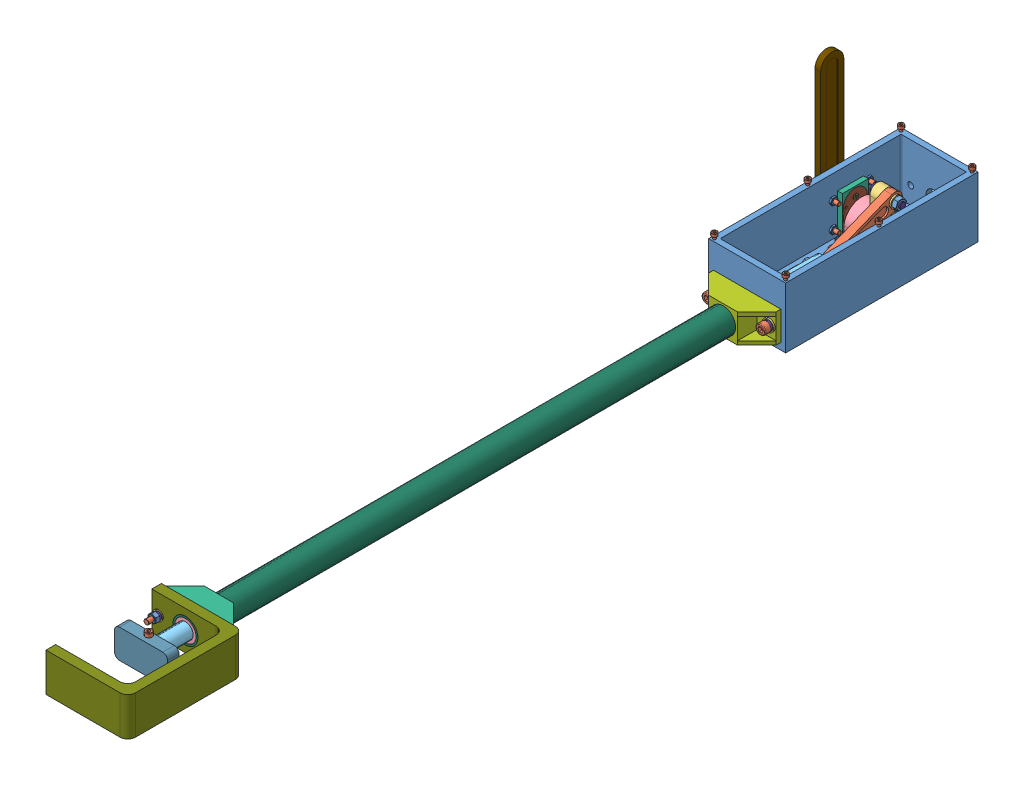
SolidWorks assembly 装夹部分, configuration 默认. Lengths in mm.
Overall size (109 161.6 894).
90 component instances, 28 part files, 159 mates.
Components (placement in the parent):
- 棘轮整体箱-1: 棘轮整体箱 [默认] at (-1.3808 -4.4563 300) size (80 63 200)
- 连杆2-1: 连杆2 [默认] at (6.6192 8.5437 195.581) x (1 0 0) z (0 -0.375 0.927025) size (8 16 96)
- 曲柄1-1: 曲柄1 [默认] at (-7.3808 8.5437 158.5) x (1 0 0) z (0 1 0) size (10 16 46)
- 棘轮轴承座-1: 棘轮轴承座 [默认] at (-17.3808 -24.4563 192) x (-1 0 0) z (0 0 -1) size (18 35 67)
- 棘轮光杆2-1: 棘轮光杆2 [默认] at (-1.3808 -6.4563 222.662) x (0 0 1) z (-1 0 0) size (703.5 16 16)
- 棘轮壳-1: 棘轮壳 [默认] at (-47.3808 1.8437 158.5) x (0 0 1) z (0 1 0) size (47 17 38)
- 棘轮轴-1: 棘轮轴 [默认] at (-33.3808 -6.4563 158.5) x (0 1 0) z (-1 0 0) size (22.6 22.6 63)
- 棘轮凸轮-1: 棘轮凸轮 [默认] at (-34.3808 7.3437 158.5) x (0 -0.826454 -0.563005) z (-1 0 0) size (8 16.5 15)
- 棘爪2-1: 棘爪2 [默认] at (-32.3808 11.8437 155.5) x (0 -0.832703 -0.55372) z (-1 0 0) size (11.61 3.86 13)
- 棘爪1-1: 棘爪1 [默认] at (-45.3808 11.8437 161.5) x (0 -0.838812 0.544421) z (1 0 0) size (11.61 3.86 13)
- 棘轮盖板-1: 棘轮盖板 [默认] at (-32.3808 -6.4563 158.5) x (0 0 1) z (1 0 0) size (25 34 2)
- cross recessed countersunk head screws gb1-1: cross recessed countersunk head screws gb1 [GB_CROSS_SCREWS_TYPE4 M3X10-8.35  H type-C] at (-29.7308 7.3437 158.5) x (-1 0 0) z (0 -0.924225 -0.381849) size (10 5.2 5.2)
- 圆锥弹簧-1: 圆锥弹簧 [默认] at (-38.3808 9.0284 150.4452) x (0.816495 -0.430855 -0.384316) z (-0.577352 -0.609319 -0.543503) size (8.02 1.7 8.11)
- 圆锥弹簧-2: 圆锥弹簧 [默认] at (-38.3808 9.0636 166.5942) x (0.838974 0.406094 -0.36223) z (-0.544172 0.626093 -0.558466) size (8.02 1.7 8.11)
- 顶片-1: 顶片 [默认] at (-1.3808 -6.4563 918.162) x (0 0 1) z (1 0 0) size (12 30 55)
- 棘轮箱杆-1: 棘轮箱杆 [默认] at (-1.3808 -6.4563 884) x (1 0 0) z (0 1 0) size (26 590 26)
- 抓手-1: 抓手 [默认] at (-36.3808 13.5437 874) x (0 -1 0) z (-1 0 0) size (40 120 85)
- 夹具销轴-1: 夹具销轴 [默认] at (-10.3808 23.5437 158.5) x (0 0 1) z (-1 0 0) size (10 12 29.2)
- 棘轮连接扳手-2: 棘轮连接扳手 [默认] at (-57.3808 -6.4563 158.5) x (0 0 -1) z (1 0 0) size (24 144 6)
- Aseembly M4X16-4: Aseembly M4X16 [默认] at (-34.9808 10.039 173.7157) x (0 0 -1) z (1 0 0) size (9.29 9.29 20)
  - hex nuts, style 1-grades ab gb-1: hex nuts, style 1-grades ab gb [GB_FASTENER_NUT_SNAB1 M4-C] at (-3.2843 0.5047 1.6) size (8.08 7 3.2)
  - hexagon socket head cap screws gb-1: hexagon socket head cap screws gb [GB_FASTENER_SCREWS_HSHCS M4X16-C] at (-3.2843 0.5047 -13.4) x (0 0 1) z (-0.418961 -0.908004 0) size (20 7 7)
  - plain washers-n series-grade a gb-1: plain washers-n series-grade a gb [GB_FASTENER_WASHER_PWNA 4] at (-3.2843 0.5047 -1.6) size (9 9 0.8)
- Aseembly M4X16-5: Aseembly M4X16 [默认] at (-34.9808 10.039 136.7157) x (0 0 -1) z (1 0 0) size (9.29 9.29 20)
  - hex nuts, style 1-grades ab gb-1: hex nuts, style 1-grades ab gb [GB_FASTENER_NUT_SNAB1 M4-C] at (-3.2843 0.5047 1.6) size (8.08 7 3.2)
  - hexagon socket head cap screws gb-1: hexagon socket head cap screws gb [GB_FASTENER_SCREWS_HSHCS M4X16-C] at (-3.2843 0.5047 -13.4) x (0 0 1) z (-0.418961 -0.908004 0) size (20 7 7)
  - plain washers-n series-grade a gb-1: plain washers-n series-grade a gb [GB_FASTENER_WASHER_PWNA 4] at (-3.2843 0.5047 -1.6) size (9 9 0.8)
- Aseembly M4X16-6: Aseembly M4X16 [默认] at (-34.9808 -15.961 136.7157) x (0 0 -1) z (1 0 0) size (9.29 9.29 20)
  - hex nuts, style 1-grades ab gb-1: hex nuts, style 1-grades ab gb [GB_FASTENER_NUT_SNAB1 M4-C] at (-3.2843 0.5047 1.6) size (8.08 7 3.2)
  - hexagon socket head cap screws gb-1: hexagon socket head cap screws gb [GB_FASTENER_SCREWS_HSHCS M4X16-C] at (-3.2843 0.5047 -13.4) x (0 0 1) z (-0.418961 -0.908004 0) size (20 7 7)
  - plain washers-n series-grade a gb-1: plain washers-n series-grade a gb [GB_FASTENER_WASHER_PWNA 4] at (-3.2843 0.5047 -1.6) size (9 9 0.8)
- Aseembly M4X16-7: Aseembly M4X16 [默认] at (-34.9808 -15.961 173.7157) x (0 0 -1) z (1 0 0) size (9.29 9.29 20)
  - hex nuts, style 1-grades ab gb-1: hex nuts, style 1-grades ab gb [GB_FASTENER_NUT_SNAB1 M4-C] at (-3.2843 0.5047 1.6) size (8.08 7 3.2)
  - hexagon socket head cap screws gb-1: hexagon socket head cap screws gb [GB_FASTENER_SCREWS_HSHCS M4X16-C] at (-3.2843 0.5047 -13.4) x (0 0 1) z (-0.418961 -0.908004 0) size (20 7 7)
  - plain washers-n series-grade a gb-1: plain washers-n series-grade a gb [GB_FASTENER_WASHER_PWNA 4] at (-3.2843 0.5047 -1.6) size (9 9 0.8)
- hexagon socket head cap screws gb-1: hexagon socket head cap screws gb [GB_FASTENER_SCREWS_HSHCS M5X25-C] at (-2.3808 -6.4563 145.5) x (0 0 1) z (-0.002807 0.999996 0) size (30 8.5 8.5)
- hex nuts, style 1-grades ab gb-2: hex nuts, style 1-grades ab gb [GB_FASTENER_NUT_SNAB1 M5-N] at (-2.3808 -6.4563 171.2) x (0.002807 -0.999996 0) z (0 0 1) size (9.24 8 4.7)
- 机箱滑动轴承16-22-1: 机箱滑动轴承16-22 [默认] at (-1.3808 -6.4563 296) x (0 0 -1) z (1 0 0) size (30 22 22)
- 机箱滑动轴承16-22-2: 机箱滑动轴承16-22 [默认] at (-1.3808 -6.4563 854) x (0 0 -1) z (0.444866 0.895597 0) size (30 22 22)
- hexagon socket head cap screws gb-2: hexagon socket head cap screws gb [GB_FASTENER_SCREWS_HSHCS M6X20-N] at (-17.3808 -36.0563 185) x (0 1 0) z (0.21636 0 0.976314) size (26 10 10)
- plain washers-n series-grade a gb-1: plain washers-n series-grade a gb [GB_FASTENER_WASHER_PWNA 6] at (-17.3808 -16.8563 185) x (0 0 -1) z (0 1 0) size (12 12 1.6)
- hex nuts, style 1-grades ab gb-3: hex nuts, style 1-grades ab gb [GB_FASTENER_NUT_SNAB1 M6-N] at (-17.3808 -11.6563 185) x (-0.789324 0 -0.613977) z (0 1 0) size (11.55 10 5.2)
- plain washers-n series-grade a gb-2: plain washers-n series-grade a gb [GB_FASTENER_WASHER_PWNA 6] at (-17.3808 -28.4563 185) x (0 0 -1) z (0 1 0) size (12 12 1.6)
- hexagon socket head cap screws gb-3: hexagon socket head cap screws gb [GB_FASTENER_SCREWS_HSHCS M6X20-N] at (-17.3808 -36.0563 132) x (0 1 0) z (0.21636 0 0.976314) size (26 10 10)
- plain washers-n series-grade a gb-3: plain washers-n series-grade a gb [GB_FASTENER_WASHER_PWNA 6] at (-17.3808 -28.4563 132) x (0 0 -1) z (0 1 0) size (12 12 1.6)
- hex nuts, style 1-grades ab gb-4: hex nuts, style 1-grades ab gb [GB_FASTENER_NUT_SNAB1 M6-N] at (-17.3808 -11.6563 132) x (-0.789324 0 -0.613977) z (0 1 0) size (11.55 10 5.2)
- plain washers-n series-grade a gb-4: plain washers-n series-grade a gb [GB_FASTENER_WASHER_PWNA 6] at (-17.3808 -16.8563 132) x (0 0 -1) z (0 1 0) size (12 12 1.6)
- 夹具销轴16-1: 夹具销轴16 [默认] at (-8.3808 -6.4563 232.662) x (0 0.733313 0.679892) z (-1 0 0) size (10 12 27.2)
- hex nuts, style 1-grades ab gb-5: hex nuts, style 1-grades ab gb [GB_FASTENER_NUT_SNAB1 M6-N] at (12.4192 23.5437 158.5) x (0 -0.789324 -0.613977) z (-1 0 0) size (11.55 10 5.2)
- plain washers-n series-grade a gb-5: plain washers-n series-grade a gb [GB_FASTENER_WASHER_PWNA 6] at (12.4192 23.5437 158.5) x (0 0 -1) z (1 0 0) size (12 12 1.6)
- plain washers-n series-grade a gb-6: plain washers-n series-grade a gb [GB_FASTENER_WASHER_PWNA 6] at (12.4192 -6.4563 232.662) x (0 0 -1) z (1 0 0) size (12 12 1.6)
- hex nuts, style 1-grades ab gb-6: hex nuts, style 1-grades ab gb [GB_FASTENER_NUT_SNAB1 M6-N] at (17.6192 -6.4563 232.662) x (0 0.789324 -0.613977) z (1 0 0) size (11.55 10 5.2)
- hexagon socket head cap screws gb-4: hexagon socket head cap screws gb [GB_FASTENER_SCREWS_HSHCS M4X35-C] at (-1.3808 12.5437 922.162) x (0 -1 0) z (0.903255 0 0.429104) size (39 7 7)
- hex nuts, style 1-grades ab gb-7: hex nuts, style 1-grades ab gb [GB_FASTENER_NUT_SNAB1 M4-C] at (-1.3808 -22.2563 922.162) x (1 0 0) z (0 1 0) size (8.08 7 3.2)
- plain washers-n series-grade a gb-7: plain washers-n series-grade a gb [GB_FASTENER_WASHER_PWNA 4] at (-1.3808 -21.4563 922.162) x (1 0 0) z (0 1 0) size (9 9 0.8)
- 焊接筒-1: 焊接筒 [默认] at (-1.3808 -6.4563 874) x (1 0 0) z (0 0 -1) size (70 30 25)
- 焊接筒2-1: 焊接筒2 [默认] at (-1.3808 -6.4563 300) size (70 30 25)
- hexagon socket head cap screws gb-5: hexagon socket head cap screws gb [GB_FASTENER_SCREWS_HSHCS M6X25-C] at (-29.3808 -6.4563 314.2) x (0 0 -1) z (1 0 0) size (31 10 10)
- plain washers-n series-grade a gb-8: plain washers-n series-grade a gb [GB_FASTENER_WASHER_PWNA 6] at (-29.3808 -6.4563 292.4) x (-1 0 0) z (0 0 -1) size (12 12 1.6)
- spring lock washers--normal type gb-1: spring lock washers--normal type gb [GB_FASTENER_WASHER_SW 6] at (-29.3808 -6.4563 290.8) x (-1 0 0) z (0 0 -1) size (9.88 9.88 1.6)
- hexagon socket head cap screws gb-6: hexagon socket head cap screws gb [GB_FASTENER_SCREWS_HSHCS M5X30-C] at (26.6192 -6.4563 861.7) x (0 0 1) z (-1 0 0) size (35 8.5 8.5)
- plain washers-n series-grade a gb-9: plain washers-n series-grade a gb [GB_FASTENER_WASHER_PWNA 5] at (26.6192 -6.4563 885) size (10 10 1)
- spring lock washers--normal type gb-2: spring lock washers--normal type gb [GB_FASTENER_WASHER_SW 5] at (26.6192 -6.4563 886.3) size (8 8 1.3)
- hex nuts, style 1-grades ab gb-8: hex nuts, style 1-grades ab gb [GB_FASTENER_NUT_SNAB1 M5-N] at (26.6192 -6.4563 891) size (9.24 8 4.7)
- hex nuts, style 1-grades ab gb-9: hex nuts, style 1-grades ab gb [GB_FASTENER_NUT_SNAB1 M6-N] at (-29.3808 -6.4563 285.6) x (-1 0 0) z (0 0 -1) size (11.55 10 5.2)
- hex nuts, style 1-grades ab gb-10: hex nuts, style 1-grades ab gb [GB_FASTENER_NUT_SNAB1 M6-N] at (26.6192 -6.4563 285.6) x (-1 0 0) z (0 0 -1) size (11.55 10 5.2)
- hexagon socket head cap screws gb-7: hexagon socket head cap screws gb [GB_FASTENER_SCREWS_HSHCS M6X25-C] at (26.6192 -6.4563 314.2) x (0 0 -1) z (1 0 0) size (31 10 10)
- plain washers-n series-grade a gb-10: plain washers-n series-grade a gb [GB_FASTENER_WASHER_PWNA 6] at (26.6192 -6.4563 305) x (-1 0 0) z (0 0 -1) size (12 12 1.6)
- spring lock washers--normal type gb-3: spring lock washers--normal type gb [GB_FASTENER_WASHER_SW 6] at (26.6192 -6.4563 306.6) x (-1 0 0) z (0 0 -1) size (9.88 9.88 1.6)
- hexagon socket head cap screws gb-8: hexagon socket head cap screws gb [GB_FASTENER_SCREWS_HSHCS M5X30-C] at (-29.3808 -6.4563 861.7) x (0 0 1) z (-1 0 0) size (35 8.5 8.5)
- plain washers-n series-grade a gb-11: plain washers-n series-grade a gb [GB_FASTENER_WASHER_PWNA 5] at (-29.3808 -6.4563 869) size (10 10 1)
- spring lock washers--normal type gb-4: spring lock washers--normal type gb [GB_FASTENER_WASHER_SW 5] at (-29.3808 -6.4563 886.3) size (8 8 1.3)
- hex nuts, style 1-grades ab gb-11: hex nuts, style 1-grades ab gb [GB_FASTENER_NUT_SNAB1 M5-N] at (-29.3808 -6.4563 891) x (0.819619 0.572908 0) z (0 0 1) size (9.24 8 4.7)
- plain washers-n series-grade a gb-12: plain washers-n series-grade a gb [GB_FASTENER_WASHER_PWNA 6] at (26.6192 -6.4563 292.4) x (-1 0 0) z (0 0 -1) size (12 12 1.6)
- spring lock washers--normal type gb-5: spring lock washers--normal type gb [GB_FASTENER_WASHER_SW 6] at (26.6192 -6.4563 290.8) x (-1 0 0) z (0 0 -1) size (9.88 9.88 1.6)
- spring lock washers--normal type gb-6: spring lock washers--normal type gb [GB_FASTENER_WASHER_SW 6] at (-29.3808 -6.4563 306.6) x (-1 0 0) z (0 0 -1) size (9.88 9.88 1.6)
- plain washers-n series-grade a gb-13: plain washers-n series-grade a gb [GB_FASTENER_WASHER_PWNA 6] at (-29.3808 -6.4563 305) x (-1 0 0) z (0 0 -1) size (12 12 1.6)
- plain washers-n series-grade a gb-14: plain washers-n series-grade a gb [GB_FASTENER_WASHER_PWNA 5] at (26.6192 -6.4563 869) size (10 10 1)
- spring lock washers--normal type gb-7: spring lock washers--normal type gb [GB_FASTENER_WASHER_SW 5] at (26.6192 -6.4563 868) size (8 8 1.3)
- plain washers-n series-grade a gb-15: plain washers-n series-grade a gb [GB_FASTENER_WASHER_PWNA 5] at (-29.3808 -6.4563 885) x (0.999691 -0.024859 0) z (0 0 1) size (10 10 1)
- spring lock washers--normal type gb-8: spring lock washers--normal type gb [GB_FASTENER_WASHER_SW 5] at (-29.3808 -6.4563 868) size (8 8 1.3)
- 棘轮箱盖板-1: 棘轮箱盖板 [默认] at (-1.3808 34.5437 200) x (0 0 1) z (0 1 0) size (200 80 3) (hidden)
- hexagon socket head cap screws gb-9: hexagon socket head cap screws gb [GB_FASTENER_SCREWS_HSHCS M3X10-C] at (35.6192 40.5437 297) x (0 -1 0) z (0 0 1) size (13 5.5 5.5)
- hexagon socket head cap screws gb-10: hexagon socket head cap screws gb [GB_FASTENER_SCREWS_HSHCS M3X10-C] at (-38.3808 40.5437 103) x (0 -1 0) z (0 0 1) size (13 5.5 5.5)
- hexagon socket head cap screws gb-11: hexagon socket head cap screws gb [GB_FASTENER_SCREWS_HSHCS M3X10-C] at (35.6192 40.5437 103) x (0 -1 0) z (0 0 1) size (13 5.5 5.5)
- hexagon socket head cap screws gb-12: hexagon socket head cap screws gb [GB_FASTENER_SCREWS_HSHCS M3X10-C] at (-38.3808 40.5437 200) x (0 -1 0) z (0 0 1) size (13 5.5 5.5)
- hexagon socket head cap screws gb-13: hexagon socket head cap screws gb [GB_FASTENER_SCREWS_HSHCS M3X10-C] at (35.6192 40.5437 200) x (0 -1 0) z (0 0 1) size (13 5.5 5.5)
- hexagon socket head cap screws gb-14: hexagon socket head cap screws gb [GB_FASTENER_SCREWS_HSHCS M3X10-C] at (-38.3808 40.5437 297) x (0 -1 0) z (0 0 1) size (13 5.5 5.5)
- cross recessed cheese head screws gb-1: cross recessed cheese head screws gb [GB_CROSS_SCREWS_TYPE2 M2.5X16-16  H type-C] at (-48.1808 1.8437 168) size (17.82 4.5 4.5)
- cross recessed cheese head screws gb-2: cross recessed cheese head screws gb [GB_CROSS_SCREWS_TYPE2 M2.5X16-16  H type-C] at (-48.1808 1.8437 149) size (17.82 4.5 4.5)
Mates (geometry in assembly coordinates):
- 同心1: concentric anti-aligned: cylinder of 棘轮整体箱-1 through (-17.3808 -34.4563 132) axis (0 1 0) radius 3.5; cylinder of 棘轮轴承座-1 through (-17.3808 -14.4563 132) axis (0 -1 0) radius 3.5
- 重合1: coincident aligned: circle of 棘轮整体箱-1; cylinder of 棘轮轴承座-1 through (-17.3808 -14.4563 185) axis (0 -1 0) radius 3.5
- 重合7: coincident anti-aligned: plane of 棘轮整体箱-1 through (-1.3808 -24.4563 300) normal (0 1 0); plane of 棘轮轴承座-1 through (-25.3808 -24.4563 125) normal (0 -1 0)
- 同心4: concentric aligned: cylinder of 曲柄1-1 through (2.6192 -6.4563 158.5) axis (-1 0 0) radius 5; cylinder of 棘轮轴承座-1 through (-2.3808 -6.4563 158.5) axis (-1 0 0) radius 5
- 同心5: concentric aligned: cylinder of 曲柄1-1 through (2.6192 23.5437 158.5) axis (-1 0 0) radius 4; cylinder of 连杆2-1 through (10.6192 23.5437 158.5) axis (-1 0 0) radius 4
- 重合4: coincident anti-aligned: plane of 连杆2-1 through (2.6192 8.5437 195.581) normal (-1 0 0); plane of 曲柄1-1 through (2.6192 23.5437 158.5) normal (1 0 0)
- 同心6: concentric aligned: cylinder of 棘轮光杆2-1 through (6.6192 -6.4563 232.662) axis (-1 0 0) radius 4; cylinder of 连杆2-1 through (10.6192 -6.4563 232.662) axis (-1 0 0) radius 4
- 同心7: concentric anti-aligned: cylinder of 棘轮整体箱-1 through (-1.3808 -6.4563 290) axis (0 0 1) radius 13; cylinder of 棘轮光杆2-1 through (-1.3808 -6.4563 926.162) axis (0 0 -1) radius 8
- 重合5: coincident anti-aligned: plane of 连杆2-1 through (2.6192 8.5437 195.581) normal (-1 0 0); plane of 棘轮光杆2-1 through (2.6192 3.5437 242.662) normal (1 0 0)
- 同心8: concentric anti-aligned: cylinder of 棘轮壳-1 through (-51.3808 10.5437 140) axis (1 0 0) radius 2.25; cylinder of 棘轮整体箱-1 through (-31.3808 10.5437 140) axis (-1 0 0) radius 2.25
- 同心9: concentric anti-aligned: cylinder of 棘轮整体箱-1 through (-31.3808 10.5437 177) axis (-1 0 0) radius 2.25; cylinder of 棘轮壳-1 through (-51.3808 10.5437 177) axis (1 0 0) radius 2.25
- 重合6: coincident anti-aligned: plane of 棘轮整体箱-1 through (-41.3808 -28.4563 100) normal (-1 0 0); plane of 棘轮壳-1 through (-41.3808 28.2056 172) normal (1 0 0)
- 同心10: concentric anti-aligned: cylinder of 棘轮壳-1 through (-44.3808 -6.4563 158.5) axis (-1 0 0) radius 7.5; cylinder of 棘轮轴-1 through (-33.3808 -6.4563 158.5) axis (1 0 0) radius 5
- 重合8: coincident anti-aligned: plane of 棘轮壳-1 through (-44.3808 1.8437 158.5) normal (1 0 0); plane of 棘轮轴-1 through (-44.3808 -6.4563 158.5) normal (-1 0 0)
- 同心11: concentric aligned: cylinder of 曲柄1-1 through (-2.3808 -6.4563 166.5) axis (0 0 -1) radius 2.5; cylinder of 棘轮轴-1 through (-2.3808 -6.4563 163.5) axis (0 0 -1) radius 2.5
- 同心12: concentric anti-aligned: cylinder of 棘轮壳-1 through (-44.3808 7.3437 158.5) axis (-1 0 0) radius 3.5; cylinder of 棘轮凸轮-1 through (-47.3808 7.3437 158.5) axis (1 0 0) radius 3.5
- 重合9: coincident anti-aligned: plane of 棘轮壳-1 through (-47.3808 1.8437 158.5) normal (-1 0 0); plane of 棘轮凸轮-1 through (-47.3808 7.3437 158.5) normal (1 0 0)
- 同心13: concentric anti-aligned: cylinder of 棘轮壳-1 through (-44.3808 11.8437 155.5) axis (-1 0 0) radius 1.5; cylinder of 棘爪2-1 through (-45.3808 11.8437 155.5) axis (1 0 0) radius 1.5
- 重合10: coincident anti-aligned: plane of 棘轮壳-1 through (-44.3808 1.8437 158.5) normal (1 0 0); plane of 棘爪2-1 through (-44.3808 11.8437 155.5) normal (-1 0 0)
- 同心14: concentric aligned: cylinder of 棘轮壳-1 through (-44.3808 11.8437 161.5) axis (-1 0 0) radius 1.5; cylinder of 棘爪1-1 through (-32.3808 11.8437 161.5) axis (-1 0 0) radius 1.5
- 重合11: coincident anti-aligned: plane of 棘轮壳-1 through (-44.3808 1.8437 158.5) normal (1 0 0); plane of 棘爪1-1 through (-44.3808 11.8437 161.5) normal (-1 0 0)
- 同心15: concentric anti-aligned: cylinder of 棘轮轴-1 through (-33.3808 -6.4563 158.5) axis (1 0 0) radius 5; cylinder of 棘轮盖板-1 through (-30.3808 -6.4563 158.5) axis (-1 0 0) radius 7.5
- 同心16: concentric anti-aligned: cylinder of 棘轮壳-1 through (-32.3808 2.5437 158.5) axis (1 0 0) radius 12.5; cylinder of 棘轮盖板-1 through (-30.3808 2.5437 158.5) axis (-1 0 0) radius 12.5
- 重合14: coincident anti-aligned: plane of 棘轮壳-1 through (-32.3808 -1.9563 158.5) normal (1 0 0); plane of 棘轮盖板-1 through (-32.3808 -1.9563 158.5) normal (-1 0 0)
- 同心19: concentric aligned: cylinder of 棘轮盖板-1 through (-30.3808 7.3437 158.5) axis (-1 0 0) radius 1.75; cylinder of cross recessed countersunk head screws gb1-1 through (-34.2466 7.3437 158.5) axis (-1 0 0) radius 1.5
- 重合17: coincident anti-aligned: plane of 棘轮盖板-1 through (-31.3808 7.3437 158.5) normal (1 0 0); circle of cross recessed countersunk head screws gb1-1
- 重合18: coincident aligned: line of 棘轮壳-1 through (-38.3808 12.1601 146.9343) axis (0 -0.665654 0.746261); line of 圆锥弹簧-1 through (-38.3808 9.0284 150.4452) axis (0 -0.665654 0.746261)
- 相切1: tangent: cylinder of 棘轮壳-1 through (-30.3808 0.5437 158.5) axis (-1 0 0) radius 11.5; face of 圆锥弹簧-1
- 重合19: coincident aligned: line of 棘轮壳-1 through (-38.3808 12.1601 170.0657) axis (0 -0.665654 -0.746261); line of 圆锥弹簧-2 through (-38.3808 9.0636 166.5942) axis (0 -0.665654 -0.746261)
- 相切2: tangent: cylinder of 棘轮壳-1 through (-30.3808 0.5437 158.5) axis (-1 0 0) radius 11.5; face of 圆锥弹簧-2
- 同心20: concentric anti-aligned: cylinder of 棘轮光杆2-1 through (-1.3808 -6.4563 926.162) axis (0 0 -1) radius 8; cylinder of 棘轮箱杆-1 through (-1.3808 -6.4563 294) axis (0 0 1) radius 13
- 重合20: coincident aligned: plane of 棘轮整体箱-1 through (-1.3808 -24.4563 294) normal (0 0 -1); plane of 棘轮箱杆-1 through (-1.3808 -6.4563 294) normal (0 0 -1)
- 同心24: concentric anti-aligned: cylinder of 棘轮箱杆-1 through (-1.3808 -6.4563 294) axis (0 0 1) radius 13; cylinder of 抓手-1 through (-1.3808 -6.4563 994.001) axis (0 0 -1) radius 13
- 重合22: coincident aligned: plane of 棘轮箱杆-1 through (-1.3808 -6.4563 884) normal (0 0 1); plane of 抓手-1 through (30.6192 -26.4563 884) normal (0 0 1)
- 同心26: concentric aligned: cylinder of 顶片-1 through (-1.3808 -6.4563 926.162) axis (0 0 -1) radius 8; circle of 抓手-1
- 平行1: parallel anti-aligned: plane of 抓手-1 through (-36.3808 -26.4563 884) normal (-1 0 0); plane of 棘轮整体箱-1 through (38.6192 -28.4563 100) normal (1 0 0)
- 同心27: concentric aligned: cylinder of 棘轮光杆2-1 through (-1.3808 -31.4563 922.162) axis (0 1 0) radius 2; cylinder of 顶片-1 through (-1.3808 -31.4563 922.162) axis (0 1 0) radius 2
- 同心28: concentric aligned: cylinder of 曲柄1-1 through (2.6192 23.5437 158.5) axis (-1 0 0) radius 4; cylinder of 夹具销轴-1 through (-10.3808 23.5437 158.5) axis (-1 0 0) radius 4
- 重合24: coincident anti-aligned: plane of 曲柄1-1 through (-7.3808 23.5437 158.5) normal (-1 0 0); plane of 夹具销轴-1 through (-7.3808 29.5437 158.5) normal (1 0 0)
- 重合26: coincident anti-aligned: plane of 棘轮轴-1 through (-67.3808 -1.7063 153.75) normal (0 0 -1); plane of 棘轮连接扳手-2 through (-54.3808 -1.7063 153.75) normal (0 0 1)
- 重合27: coincident aligned: plane of 棘轮轴-1 through (-60.3808 -6.4563 158.5) normal (-1 0 0); plane of 棘轮连接扳手-2 through (-60.3808 -6.4563 158.5) normal (-1 0 0)
- 重合28: coincident anti-aligned: plane of 棘轮轴-1 through (-67.3808 -11.2063 163.25) normal (0 -1 0); plane of 棘轮连接扳手-2 through (-54.3808 -11.2063 153.75) normal (0 1 0)
- 同心341: concentric aligned: cylinder of 棘轮壳-1 through (-44.3808 -15.4563 177) axis (-1 0 0) radius 4; cylinder of Aseembly M4X16-7/hexagon socket head cap screws gb-1 through (-28.3808 -15.4563 177) axis (-1 0 0) radius 2
- 重合341: coincident anti-aligned: circle of 棘轮壳-1; plane of Aseembly M4X16-7/hexagon socket head cap screws gb-1 through (-44.3808 -15.4563 177) normal (1 0 0)
- 同心351: concentric anti-aligned: cylinder of 棘轮壳-1 through (-51.3808 -15.4563 140) axis (1 0 0) radius 2.25; cylinder of Aseembly M4X16-6/hexagon socket head cap screws gb-1 through (-28.3808 -15.4563 140) axis (-1 0 0) radius 2
- 同心361: concentric anti-aligned: cylinder of 棘轮壳-1 through (-51.3808 10.5437 140) axis (1 0 0) radius 2.25; cylinder of Aseembly M4X16-5/hexagon socket head cap screws gb-1 through (-28.3808 10.5437 140) axis (-1 0 0) radius 2
- 重合351: coincident anti-aligned: plane of 棘轮壳-1 through (-44.3808 10.5437 140) normal (-1 0 0); plane of Aseembly M4X16-5/hexagon socket head cap screws gb-1 through (-44.3808 10.5437 140) normal (1 0 0)
- 重合361: coincident anti-aligned: plane of 棘轮壳-1 through (-44.3808 -15.4563 140) normal (-1 0 0); plane of Aseembly M4X16-6/hexagon socket head cap screws gb-1 through (-44.3808 -15.4563 140) normal (1 0 0)
- 同心411: concentric anti-aligned: cylinder of hexagon socket head cap screws gb-1 through (-2.3808 -6.4563 175.5) axis (0 0 -1) radius 2.5; cylinder of hex nuts, style 1-grades ab gb-2 through (-2.3808 -6.4563 166.5) axis (0 0 1) radius 2.067
- 同心421: concentric aligned: cylinder of 曲柄1-1 through (-2.3808 -6.4563 166.5) axis (0 0 -1) radius 2.5; cylinder of hexagon socket head cap screws gb-1 through (-2.3808 -6.4563 175.5) axis (0 0 -1) radius 2.5
- 重合391: coincident anti-aligned: plane of 曲柄1-1 through (2.6192 -6.4563 150.5) normal (0 0 -1); plane of hexagon socket head cap screws gb-1 through (-2.3808 -6.4563 150.5) normal (0 0 1)
- 重合401: coincident anti-aligned: plane of 曲柄1-1 through (2.6192 23.5437 166.5) normal (0 0 1); plane of hex nuts, style 1-grades ab gb-2 through (-2.3679 -11.0751 166.5) normal (0 0 -1)
- 重合42: coincident aligned: plane of 抓手-1 through (30.6192 -26.4563 884) normal (0 0 1); plane of 机箱滑动轴承16-22-2 through (-1.3808 -6.4563 884) normal (0 0 1)
- 同心422: concentric anti-aligned: cylinder of hexagon socket head cap screws gb-2 through (-17.3808 -10.0563 185) axis (0 -1 0) radius 3; cylinder of plain washers-n series-grade a gb-2 through (-17.3808 -30.0563 185) axis (0 1 0) radius 3.2
- 重合402: coincident anti-aligned: plane of hexagon socket head cap screws gb-2 through (-17.3808 -30.0563 185) normal (0 1 0); plane of plain washers-n series-grade a gb-2 through (-17.3808 -30.0563 185) normal (0 -1 0)
- 同心423: concentric anti-aligned: cylinder of hexagon socket head cap screws gb-2 through (-17.3808 -10.0563 185) axis (0 -1 0) radius 3; cylinder of plain washers-n series-grade a gb-1 through (-17.3808 -18.4563 185) axis (0 1 0) radius 3.2
- 同心424: concentric anti-aligned: cylinder of hexagon socket head cap screws gb-2 through (-17.3808 -10.0563 185) axis (0 -1 0) radius 3; cylinder of hex nuts, style 1-grades ab gb-3 through (-17.3808 -16.8563 185) axis (0 1 0) radius 2.4585
- 重合403: coincident anti-aligned: plane of plain washers-n series-grade a gb-1 through (-17.3808 -16.8563 185) normal (0 1 0); plane of hex nuts, style 1-grades ab gb-3 through (-11.2411 -16.8563 177.1068) normal (0 -1 0)
- 同心425: concentric aligned: cylinder of 棘轮轴承座-1 through (-17.3808 -14.4563 185) axis (0 -1 0) radius 3.5; cylinder of hexagon socket head cap screws gb-2 through (-17.3808 -10.0563 185) axis (0 -1 0) radius 3
- 重合404: coincident aligned: plane of 棘轮轴承座-1 through (-2.3808 -18.4563 192) normal (0 1 0); circle of plain washers-n series-grade a gb-1
- 重合405: coincident anti-aligned: plane of 棘轮整体箱-1 through (-41.3808 -28.4563 100) normal (0 -1 0); circle of plain washers-n series-grade a gb-2
- 同心426: concentric anti-aligned: cylinder of hexagon socket head cap screws gb-3 through (-17.3808 -10.0563 132) axis (0 -1 0) radius 3; cylinder of plain washers-n series-grade a gb-3 through (-17.3808 -30.0563 132) axis (0 1 0) radius 3.2
- 重合406: coincident anti-aligned: plane of hexagon socket head cap screws gb-3 through (-17.3808 -30.0563 132) normal (0 1 0); plane of plain washers-n series-grade a gb-3 through (-17.3808 -30.0563 132) normal (0 -1 0)
- 重合407: coincident anti-aligned: plane of 棘轮整体箱-1 through (-41.3808 -28.4563 100) normal (0 -1 0); plane of plain washers-n series-grade a gb-3 through (-17.3808 -28.4563 132) normal (0 1 0)
- 同心427: concentric anti-aligned: cylinder of 棘轮整体箱-1 through (-17.3808 -34.4563 132) axis (0 1 0) radius 3.5; cylinder of hexagon socket head cap screws gb-3 through (-17.3808 -10.0563 132) axis (0 -1 0) radius 3
- 同心428: concentric aligned: cylinder of hex nuts, style 1-grades ab gb-4 through (-17.3808 -16.8563 132) axis (0 1 0) radius 2.4585; cylinder of plain washers-n series-grade a gb-4 through (-17.3808 -18.4563 132) axis (0 1 0) radius 3.2
- 重合408: coincident anti-aligned: plane of hex nuts, style 1-grades ab gb-4 through (-11.2411 -16.8563 124.1068) normal (0 -1 0); plane of plain washers-n series-grade a gb-4 through (-17.3808 -16.8563 132) normal (0 1 0)
- 重合409: coincident anti-aligned: plane of 棘轮轴承座-1 through (-2.3808 -18.4563 192) normal (0 1 0); plane of plain washers-n series-grade a gb-4 through (-17.3808 -18.4563 132) normal (0 -1 0)
- 同心429: concentric anti-aligned: cylinder of hexagon socket head cap screws gb-3 through (-17.3808 -10.0563 132) axis (0 -1 0) radius 3; cylinder of hex nuts, style 1-grades ab gb-4 through (-17.3808 -16.8563 132) axis (0 1 0) radius 2.4585
- 同心430: concentric aligned: cylinder of 连杆2-1 through (10.6192 -6.4563 232.662) axis (-1 0 0) radius 8; cylinder of 夹具销轴16-1 through (-8.3808 -6.4563 232.662) axis (-1 0 0) radius 4
- 同心431: concentric aligned: cylinder of 棘轮光杆2-1 through (6.6192 -6.4563 232.662) axis (-1 0 0) radius 4; cylinder of 夹具销轴16-1 through (-8.3808 -6.4563 232.662) axis (-1 0 0) radius 4
- 重合410: coincident anti-aligned: plane of 棘轮光杆2-1 through (-5.3808 3.5437 242.662) normal (-1 0 0); plane of 夹具销轴16-1 through (-5.3808 -2.377 228.2621) normal (1 0 0)
- 重合411: coincident anti-aligned: cylinder of 夹具销轴-1 through (-10.3808 23.5437 158.5) axis (-1 0 0) radius 3; circle of hex nuts, style 1-grades ab gb-5
- 同心435: concentric anti-aligned: cylinder of 夹具销轴-1 through (-10.3808 23.5437 158.5) axis (-1 0 0) radius 3; cylinder of plain washers-n series-grade a gb-5 through (10.8192 23.5437 158.5) axis (1 0 0) radius 6
- 重合412: coincident anti-aligned: plane of 夹具销轴-1 through (10.8192 27.5437 158.5) normal (1 0 0); plane of plain washers-n series-grade a gb-5 through (10.8192 23.5437 158.5) normal (-1 0 0)
- 重合413: coincident anti-aligned: plane of hex nuts, style 1-grades ab gb-5 through (12.4192 29.6835 150.6068) normal (-1 0 0); plane of plain washers-n series-grade a gb-5 through (12.4192 23.5437 158.5) normal (1 0 0)
- 同心436: concentric aligned: cylinder of plain washers-n series-grade a gb-6 through (10.8192 -6.4563 232.662) axis (1 0 0) radius 3.2; cylinder of hex nuts, style 1-grades ab gb-6 through (12.4192 -6.4563 232.662) axis (1 0 0) radius 2.4585
- 同心437: concentric anti-aligned: cylinder of 夹具销轴16-1 through (-8.3808 -6.4563 232.662) axis (-1 0 0) radius 3; cylinder of hex nuts, style 1-grades ab gb-6 through (12.4192 -6.4563 232.662) axis (1 0 0) radius 2.4585
- 重合414: coincident anti-aligned: plane of plain washers-n series-grade a gb-6 through (10.8192 -6.4563 232.662) normal (-1 0 0); plane of 夹具销轴16-1 through (10.8192 -3.7367 229.7287) normal (1 0 0)
- 重合415: coincident anti-aligned: plane of plain washers-n series-grade a gb-6 through (12.4192 -6.4563 232.662) normal (1 0 0); plane of hex nuts, style 1-grades ab gb-6 through (12.4192 -12.5961 224.7687) normal (-1 0 0)
- 同心439: concentric aligned: cylinder of 顶片-1 through (-1.3808 -31.4563 922.162) axis (0 1 0) radius 2; cylinder of hexagon socket head cap screws gb-4 through (-1.3808 -26.4563 922.162) axis (0 1 0) radius 2
- 重合417: coincident anti-aligned: plane of 顶片-1 through (21.1192 8.5437 930.162) normal (0 1 0); plane of hexagon socket head cap screws gb-4 through (-1.3808 8.5437 922.162) normal (0 -1 0)
- 同心440: concentric aligned: cylinder of hex nuts, style 1-grades ab gb-7 through (-1.3808 -25.4563 922.162) axis (0 1 0) radius 1.621; cylinder of plain washers-n series-grade a gb-7 through (-1.3808 -22.2563 922.162) axis (0 1 0) radius 2.15
- 重合418: coincident anti-aligned: plane of hex nuts, style 1-grades ab gb-7 through (2.6606 -22.2563 922.162) normal (0 1 0); plane of plain washers-n series-grade a gb-7 through (-1.3808 -22.2563 922.162) normal (0 -1 0)
- 同心441: concentric aligned: cylinder of hexagon socket head cap screws gb-4 through (-1.3808 -26.4563 922.162) axis (0 1 0) radius 2; cylinder of hex nuts, style 1-grades ab gb-7 through (-1.3808 -25.4563 922.162) axis (0 1 0) radius 1.621
- 重合419: coincident anti-aligned: plane of 顶片-1 through (21.1192 -21.4563 930.162) normal (0 -1 0); plane of plain washers-n series-grade a gb-7 through (-1.3808 -21.4563 922.162) normal (0 1 0)
- 同心442: concentric anti-aligned: cylinder of 焊接筒-1 through (26.6192 -6.4563 869) axis (0 0 1) radius 2.75; cylinder of 抓手-1 through (26.6192 -6.4563 894) axis (0 0 -1) radius 3.25
- 同心443: concentric anti-aligned: cylinder of 焊接筒-1 through (-29.3808 -6.4563 869) axis (0 0 1) radius 2.75; cylinder of 抓手-1 through (-29.3808 -6.4563 894) axis (0 0 -1) radius 3.25
- 重合420: coincident anti-aligned: plane of 抓手-1 through (-36.3808 -26.4563 874) normal (0 0 -1); plane of 焊接筒-1 through (-1.3808 -6.4563 874) normal (0 0 1)
- 同心444: concentric anti-aligned: cylinder of 棘轮整体箱-1 through (26.6192 -6.4563 290) axis (0 0 1) radius 3.3; cylinder of 焊接筒2-1 through (26.6192 -6.4563 305) axis (0 0 -1) radius 3.3
- 同心445: concentric anti-aligned: cylinder of 棘轮整体箱-1 through (-29.3808 -6.4563 290) axis (0 0 1) radius 3.3; cylinder of 焊接筒2-1 through (-29.3808 -6.4563 305) axis (0 0 -1) radius 3.3
- 重合421: coincident: plane of 棘轮整体箱-1 through (-1.3808 -4.4563 300) normal (0 0 1); line of 焊接筒2-1 through (33.6192 8.5437 300) axis (-1 0 0)
- 同心446: concentric anti-aligned: cylinder of hexagon socket head cap screws gb-7 through (26.6192 -6.4563 283.2) axis (0 0 1) radius 3; cylinder of plain washers-n series-grade a gb-10 through (26.6192 -6.4563 306.6) axis (0 0 -1) radius 3.2
- 同心447: concentric anti-aligned: cylinder of hexagon socket head cap screws gb-7 through (26.6192 -6.4563 283.2) axis (0 0 1) radius 3; cylinder of spring lock washers--normal type gb-3 through (26.6192 -6.4563 308.2) axis (0 0 -1) radius 3.34
- 重合422: coincident anti-aligned: plane of plain washers-n series-grade a gb-10 through (26.6192 -6.4563 306.6) normal (0 0 1); plane of spring lock washers--normal type gb-3 through (26.6192 -6.4563 306.6) normal (0 0 -1)
- 重合423: coincident anti-aligned: plane of hexagon socket head cap screws gb-7 through (26.6192 -6.4563 308.2) normal (0 0 -1); plane of spring lock washers--normal type gb-3 through (26.6192 -6.4563 308.2) normal (0 0 1)
- 同心448: concentric anti-aligned: cylinder of hex nuts, style 1-grades ab gb-10 through (26.6192 -6.4563 290.8) axis (0 0 -1) radius 2.4585; cylinder of hexagon socket head cap screws gb-7 through (26.6192 -6.4563 283.2) axis (0 0 1) radius 3
- 同心449: concentric anti-aligned: cylinder of hexagon socket head cap screws gb-7 through (26.6192 -6.4563 283.2) axis (0 0 1) radius 3; cylinder of plain washers-n series-grade a gb-12 through (26.6192 -6.4563 294) axis (0 0 -1) radius 3.2
- 同心450: concentric anti-aligned: cylinder of hexagon socket head cap screws gb-7 through (26.6192 -6.4563 283.2) axis (0 0 1) radius 3; cylinder of spring lock washers--normal type gb-5 through (26.6192 -6.4563 292.4) axis (0 0 -1) radius 3.34
- 重合425: coincident anti-aligned: plane of plain washers-n series-grade a gb-12 through (26.6192 -6.4563 292.4) normal (0 0 -1); plane of spring lock washers--normal type gb-5 through (26.6192 -6.4563 292.4) normal (0 0 1)
- 重合426: coincident anti-aligned: plane of hex nuts, style 1-grades ab gb-10 through (26.6192 -16.4563 290.8) normal (0 0 1); plane of spring lock washers--normal type gb-5 through (26.6192 -6.4563 290.8) normal (0 0 -1)
- 同心451: concentric anti-aligned: cylinder of 焊接筒2-1 through (26.6192 -6.4563 305) axis (0 0 -1) radius 3.3; cylinder of hexagon socket head cap screws gb-7 through (26.6192 -6.4563 283.2) axis (0 0 1) radius 3
- 重合427: coincident anti-aligned: plane of 焊接筒2-1 through (-1.3808 -6.4563 305) normal (0 0 1); plane of plain washers-n series-grade a gb-10 through (26.6192 -6.4563 305) normal (0 0 -1)
- 重合428: coincident anti-aligned: plane of 棘轮整体箱-1 through (-1.3808 -24.4563 294) normal (0 0 -1); plane of plain washers-n series-grade a gb-12 through (26.6192 -6.4563 294) normal (0 0 1)
- 同心452: concentric anti-aligned: cylinder of hexagon socket head cap screws gb-5 through (-29.3808 -6.4563 283.2) axis (0 0 1) radius 3; cylinder of plain washers-n series-grade a gb-8 through (-29.3808 -6.4563 294) axis (0 0 -1) radius 3.2
- 同心453: concentric anti-aligned: cylinder of hexagon socket head cap screws gb-5 through (-29.3808 -6.4563 283.2) axis (0 0 1) radius 3; cylinder of spring lock washers--normal type gb-1 through (-29.3808 -6.4563 292.4) axis (0 0 -1) radius 3.34
- 同心454: concentric anti-aligned: cylinder of hexagon socket head cap screws gb-5 through (-29.3808 -6.4563 283.2) axis (0 0 1) radius 3; cylinder of hex nuts, style 1-grades ab gb-9 through (-29.3808 -6.4563 290.8) axis (0 0 -1) radius 2.4585
- 重合429: coincident anti-aligned: plane of spring lock washers--normal type gb-1 through (-29.3808 -6.4563 290.8) normal (0 0 -1); plane of hex nuts, style 1-grades ab gb-9 through (-29.3808 -16.4563 290.8) normal (0 0 1)
- 重合430: coincident anti-aligned: plane of plain washers-n series-grade a gb-8 through (-29.3808 -6.4563 292.4) normal (0 0 -1); plane of spring lock washers--normal type gb-1 through (-29.3808 -6.4563 292.4) normal (0 0 1)
- 同心455: concentric anti-aligned: cylinder of hexagon socket head cap screws gb-5 through (-29.3808 -6.4563 283.2) axis (0 0 1) radius 3; cylinder of plain washers-n series-grade a gb-13 through (-29.3808 -6.4563 306.6) axis (0 0 -1) radius 3.2
- 同心456: concentric anti-aligned: cylinder of hexagon socket head cap screws gb-5 through (-29.3808 -6.4563 283.2) axis (0 0 1) radius 3; cylinder of spring lock washers--normal type gb-6 through (-29.3808 -6.4563 308.2) axis (0 0 -1) radius 3.34
- 重合431: coincident anti-aligned: plane of spring lock washers--normal type gb-6 through (-29.3808 -6.4563 306.6) normal (0 0 -1); plane of plain washers-n series-grade a gb-13 through (-29.3808 -6.4563 306.6) normal (0 0 1)
- 重合432: coincident anti-aligned: plane of hexagon socket head cap screws gb-5 through (-29.3808 -6.4563 308.2) normal (0 0 -1); plane of spring lock washers--normal type gb-6 through (-29.3808 -6.4563 308.2) normal (0 0 1)
- 同心457: concentric anti-aligned: cylinder of 焊接筒2-1 through (-29.3808 -6.4563 305) axis (0 0 -1) radius 3.3; cylinder of hexagon socket head cap screws gb-5 through (-29.3808 -6.4563 283.2) axis (0 0 1) radius 3
- 重合433: coincident anti-aligned: plane of 焊接筒2-1 through (-1.3808 -6.4563 305) normal (0 0 1); plane of plain washers-n series-grade a gb-13 through (-29.3808 -6.4563 305) normal (0 0 -1)
- 重合434: coincident anti-aligned: plane of 棘轮整体箱-1 through (-1.3808 -24.4563 294) normal (0 0 -1); plane of plain washers-n series-grade a gb-8 through (-29.3808 -6.4563 294) normal (0 0 1)
- 同心458: concentric anti-aligned: cylinder of hexagon socket head cap screws gb-6 through (26.6192 -6.4563 896.7) axis (0 0 -1) radius 2.5; cylinder of plain washers-n series-grade a gb-9 through (26.6192 -6.4563 884) axis (0 0 1) radius 2.65
- 同心459: concentric anti-aligned: cylinder of hexagon socket head cap screws gb-6 through (26.6192 -6.4563 896.7) axis (0 0 -1) radius 2.5; cylinder of spring lock washers--normal type gb-2 through (26.6192 -6.4563 885) axis (0 0 1) radius 2.7
- 同心460: concentric anti-aligned: cylinder of hexagon socket head cap screws gb-6 through (26.6192 -6.4563 896.7) axis (0 0 -1) radius 2.5; cylinder of plain washers-n series-grade a gb-14 through (26.6192 -6.4563 868) axis (0 0 1) radius 2.65
- 同心461: concentric anti-aligned: cylinder of hexagon socket head cap screws gb-6 through (26.6192 -6.4563 896.7) axis (0 0 -1) radius 2.5; cylinder of spring lock washers--normal type gb-7 through (26.6192 -6.4563 866.7) axis (0 0 1) radius 2.7
- 同心462: concentric anti-aligned: cylinder of hexagon socket head cap screws gb-6 through (26.6192 -6.4563 896.7) axis (0 0 -1) radius 2.5; cylinder of hex nuts, style 1-grades ab gb-8 through (26.6192 -6.4563 886.3) axis (0 0 1) radius 2.067
- 重合435: coincident anti-aligned: plane of plain washers-n series-grade a gb-14 through (26.6192 -6.4563 868) normal (0 0 -1); plane of spring lock washers--normal type gb-7 through (26.6192 -6.4563 868) normal (0 0 1)
- 重合436: coincident anti-aligned: plane of hexagon socket head cap screws gb-6 through (26.6192 -6.4563 866.7) normal (0 0 1); plane of spring lock washers--normal type gb-7 through (26.6192 -6.4563 866.7) normal (0 0 -1)
- 重合437: coincident anti-aligned: plane of spring lock washers--normal type gb-2 through (26.6192 -6.4563 886.3) normal (0 0 1); plane of hex nuts, style 1-grades ab gb-8 through (31.238 -6.4563 886.3) normal (0 0 -1)
- 重合438: coincident anti-aligned: plane of plain washers-n series-grade a gb-9 through (26.6192 -6.4563 885) normal (0 0 1); plane of spring lock washers--normal type gb-2 through (26.6192 -6.4563 885) normal (0 0 -1)
- 同心463: concentric anti-aligned: cylinder of 焊接筒-1 through (26.6192 -6.4563 869) axis (0 0 1) radius 2.75; cylinder of hexagon socket head cap screws gb-6 through (26.6192 -6.4563 896.7) axis (0 0 -1) radius 2.5
- 重合439: coincident anti-aligned: plane of 焊接筒-1 through (-1.3808 -6.4563 869) normal (0 0 -1); plane of plain washers-n series-grade a gb-14 through (26.6192 -6.4563 869) normal (0 0 1)
- 重合440: coincident anti-aligned: plane of 抓手-1 through (30.6192 -26.4563 884) normal (0 0 1); plane of plain washers-n series-grade a gb-9 through (26.6192 -6.4563 884) normal (0 0 -1)
- 同心464: concentric anti-aligned: cylinder of hexagon socket head cap screws gb-8 through (-29.3808 -6.4563 896.7) axis (0 0 -1) radius 2.5; cylinder of plain washers-n series-grade a gb-15 through (-29.3808 -6.4563 884) axis (0 0 1) radius 2.65
- 同心465: concentric anti-aligned: cylinder of hexagon socket head cap screws gb-8 through (-29.3808 -6.4563 896.7) axis (0 0 -1) radius 2.5; cylinder of plain washers-n series-grade a gb-11 through (-29.3808 -6.4563 868) axis (0 0 1) radius 2.65
- 同心467: concentric anti-aligned: cylinder of hexagon socket head cap screws gb-8 through (-29.3808 -6.4563 896.7) axis (0 0 -1) radius 2.5; cylinder of spring lock washers--normal type gb-8 through (-29.3808 -6.4563 866.7) axis (0 0 1) radius 2.7
- 同心468: concentric anti-aligned: cylinder of hexagon socket head cap screws gb-8 through (-29.3808 -6.4563 896.7) axis (0 0 -1) radius 2.5; cylinder of spring lock washers--normal type gb-4 through (-29.3808 -6.4563 885) axis (0 0 1) radius 2.7
- 同心469: concentric anti-aligned: cylinder of hexagon socket head cap screws gb-8 through (-29.3808 -6.4563 896.7) axis (0 0 -1) radius 2.5; cylinder of hex nuts, style 1-grades ab gb-11 through (-29.3808 -6.4563 886.3) axis (0 0 1) radius 2.067
- 重合441: coincident anti-aligned: plane of hexagon socket head cap screws gb-8 through (-29.3808 -6.4563 866.7) normal (0 0 1); plane of spring lock washers--normal type gb-8 through (-29.3808 -6.4563 866.7) normal (0 0 -1)
- 重合442: coincident aligned: circle of plain washers-n series-grade a gb-11; plane of spring lock washers--normal type gb-8 through (-29.3808 -6.4563 868) normal (0 0 1)
- 重合443: coincident anti-aligned: plane of spring lock washers--normal type gb-4 through (-29.3808 -6.4563 886.3) normal (0 0 1); plane of hex nuts, style 1-grades ab gb-11 through (-25.5952 -3.8102 886.3) normal (0 0 -1)
- 重合444: coincident anti-aligned: plane of spring lock washers--normal type gb-4 through (-29.3808 -6.4563 885) normal (0 0 -1); plane of plain washers-n series-grade a gb-15 through (-29.3808 -6.4563 885) normal (0 0 1)
- 同心470: concentric anti-aligned: cylinder of 焊接筒-1 through (-29.3808 -6.4563 869) axis (0 0 1) radius 2.75; cylinder of hexagon socket head cap screws gb-8 through (-29.3808 -6.4563 896.7) axis (0 0 -1) radius 2.5
- 重合445: coincident anti-aligned: plane of 焊接筒-1 through (-1.3808 -6.4563 869) normal (0 0 -1); plane of plain washers-n series-grade a gb-11 through (-29.3808 -6.4563 869) normal (0 0 1)
- 重合446: coincident anti-aligned: plane of 抓手-1 through (30.6192 -26.4563 884) normal (0 0 1); plane of plain washers-n series-grade a gb-15 through (-29.3808 -6.4563 884) normal (0 0 -1)
- 同心471: concentric anti-aligned: cylinder of 棘轮整体箱-1 through (35.6192 34.5437 297) axis (0 1 0) radius 1.25; cylinder of 棘轮箱盖板-1 through (35.6192 37.5437 297) axis (0 -1 0) radius 1.65
- 同心472: concentric anti-aligned: cylinder of 棘轮整体箱-1 through (-38.3808 34.5437 297) axis (0 1 0) radius 1.25; cylinder of 棘轮箱盖板-1 through (-38.3808 37.5437 297) axis (0 -1 0) radius 1.65
- 重合447: coincident anti-aligned: plane of 棘轮整体箱-1 through (-1.3808 34.5437 300) normal (0 1 0); plane of 棘轮箱盖板-1 through (-1.3808 34.5437 200) normal (0 -1 0)
- 同心473: concentric anti-aligned: cylinder of 棘轮箱盖板-1 through (35.6192 37.5437 297) axis (0 -1 0) radius 1.65; cylinder of hexagon socket head cap screws gb-9 through (35.6192 27.5437 297) axis (0 1 0) radius 1.5
- 重合448: coincident anti-aligned: plane of 棘轮箱盖板-1 through (-1.3808 37.5437 200) normal (0 1 0); plane of hexagon socket head cap screws gb-9 through (35.6192 37.5437 297) normal (0 -1 0)
- 重合449: coincident aligned: plane of hexagon socket head cap screws gb-13 through (35.6192 40.5437 200) normal (0 1 0); plane of hexagon socket head cap screws gb-12 through (-38.3808 40.5437 200) normal (0 1 0)
- 重合450: coincident aligned: plane of hexagon socket head cap screws gb-13 through (35.6192 40.5437 200) normal (0 1 0); plane of hexagon socket head cap screws gb-11 through (35.6192 40.5437 103) normal (0 1 0)
- 重合451: coincident aligned: plane of hexagon socket head cap screws gb-13 through (35.6192 40.5437 200) normal (0 1 0); plane of hexagon socket head cap screws gb-14 through (-38.3808 40.5437 297) normal (0 1 0)
- 重合452: coincident aligned: plane of hexagon socket head cap screws gb-13 through (35.6192 40.5437 200) normal (0 1 0); plane of hexagon socket head cap screws gb-10 through (-38.3808 40.5437 103) normal (0 1 0)
- 同心474: concentric anti-aligned: cylinder of 棘轮箱盖板-1 through (35.6192 37.5437 200) axis (0 -1 0) radius 1.65; cylinder of hexagon socket head cap screws gb-13 through (35.6192 27.5437 200) axis (0 1 0) radius 1.5
- 同心475: concentric anti-aligned: cylinder of 棘轮箱盖板-1 through (-38.3808 37.5437 297) axis (0 -1 0) radius 1.65; cylinder of hexagon socket head cap screws gb-14 through (-38.3808 27.5437 297) axis (0 1 0) radius 1.5
- 同心476: concentric aligned: circle of 棘轮箱盖板-1; cylinder of hexagon socket head cap screws gb-12 through (-38.3808 27.5437 200) axis (0 1 0) radius 1.5
- 同心477: concentric anti-aligned: cylinder of 棘轮箱盖板-1 through (35.6192 37.5437 103) axis (0 -1 0) radius 1.65; cylinder of hexagon socket head cap screws gb-11 through (35.6192 27.5437 103) axis (0 1 0) radius 1.5
- 同心478: concentric aligned: circle of 棘轮箱盖板-1; cylinder of hexagon socket head cap screws gb-10 through (-38.3808 27.5437 103) axis (0 1 0) radius 1.5
- 重合453: coincident anti-aligned: plane of 棘轮箱盖板-1 through (-1.3808 37.5437 200) normal (0 1 0); plane of hexagon socket head cap screws gb-11 through (35.6192 37.5437 103) normal (0 -1 0)
- 同心481: concentric anti-aligned: cylinder of 棘轮壳-1 through (-44.3808 1.8437 149) axis (-1 0 0) radius 1.5; cylinder of cross recessed cheese head screws gb-2 through (-43.665 1.8437 149) axis (1 0 0) radius 1.25
- 同心482: concentric anti-aligned: cylinder of 棘轮壳-1 through (-44.3808 1.8437 168) axis (-1 0 0) radius 1.5; cylinder of cross recessed cheese head screws gb-1 through (-43.665 1.8437 168) axis (1 0 0) radius 1.25
- 重合454: coincident anti-aligned: plane of 棘轮壳-1 through (-46.3808 1.8437 149) normal (-1 0 0); plane of cross recessed cheese head screws gb-2 through (-46.3808 3.3937 149) normal (1 0 0)
- 重合455: coincident anti-aligned: plane of 棘轮壳-1 through (-46.3808 1.8437 168) normal (-1 0 0); plane of cross recessed cheese head screws gb-1 through (-46.3808 3.3937 168) normal (1 0 0)
